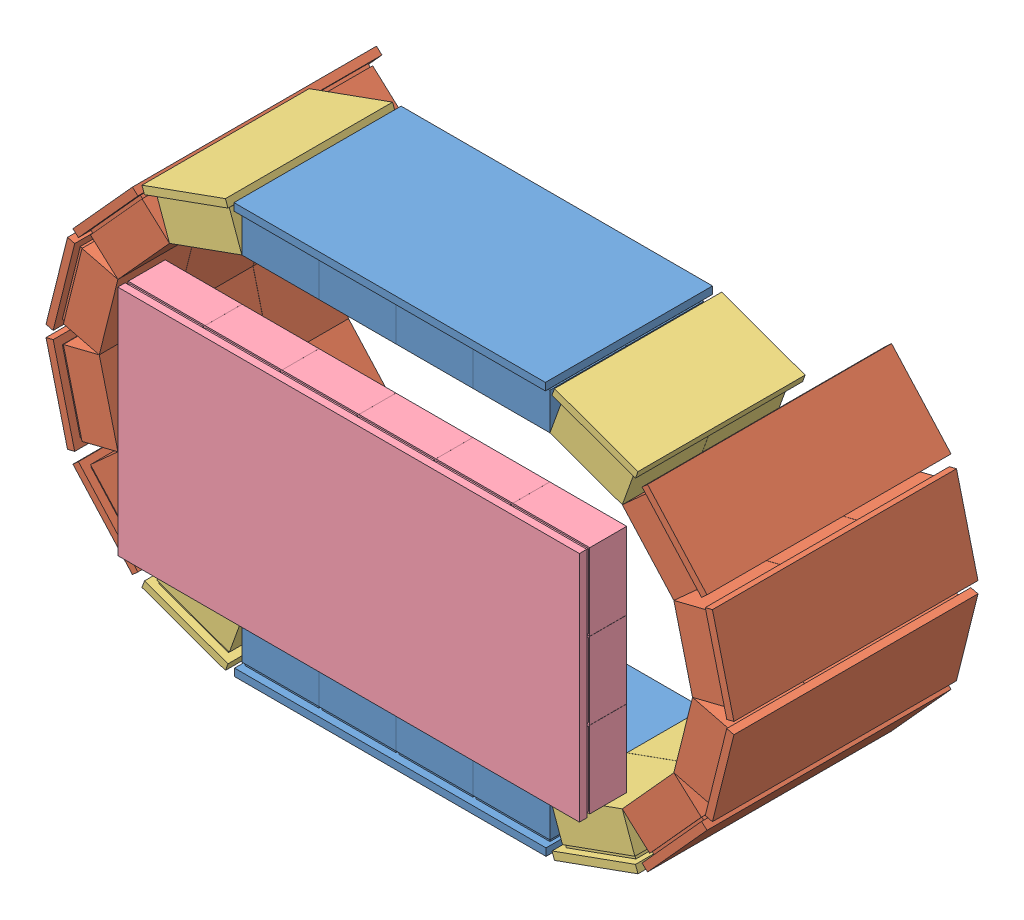
SolidWorks assembly detectorassem, configuration Default. Lengths in mm.
Overall size (517.67 317.54 193).
17 component instances, 4 part files, 15 mates.
Components (placement in the parent):
- 52mmTOPBOTTOM-1: 52mmTOPBOTTOM [Default] at (-69.8528 -35.4842 8.7442) size (210.55 32 113)
- SideDetector-1: SideDetector [Default] at (215.9367 233.9438 -54.2197) x (-0.242515 0.970148 0) z (0 0 1) size (268 155.36 165)
  - 52mmX4-1: 52mmX4 [Default] at (-99.1405 6.5957 36.9639) size (60 32 165)
  - 52mmX4-2: 52mmX4 [Default] at (-35.1412 22.594 36.9639) x (0.882373 0.47055 0) z (0 0 1) size (60 32 165)
  - 52mmX4-3: 52mmX4 [Default] at (-163.1399 22.594 36.9639) x (0.882373 -0.47055 0) z (0 0 1) size (60 32 165)
  - 52mmX4-4: 52mmX4 [Default] at (-212.0831 66.8254 36.9639) x (0.557166 -0.830401 0) z (0 0 1) size (60 32 165)
  - 52mmX3-1: 52mmX3 [Default] at (-234.4563 128.8843 62.9639) x (0.100883 -0.994898 0) z (0 0 1) size (60 32 113)
  - 52mmX3-2: 52mmX3 [Default] at (13.802 66.8254 62.9639) x (0.557166 0.830401 0) z (0 0 1) size (60 32 113)
- SideDetector-2: SideDetector [Default] at (-199.3424 -27.5859 -54.2197) x (0.242515 -0.970148 0) z (0 0 1) size (268 155.36 165)
  - 52mmX4-1: 52mmX4 [Default] at (-99.1405 6.5957 36.9639) size (60 32 165)
  - 52mmX4-2: 52mmX4 [Default] at (-35.1412 22.594 36.9639) x (0.882373 0.47055 0) z (0 0 1) size (60 32 165)
  - 52mmX4-3: 52mmX4 [Default] at (-163.1399 22.594 36.9639) x (0.882373 -0.47055 0) z (0 0 1) size (60 32 165)
  - 52mmX4-4: 52mmX4 [Default] at (-212.0831 66.8254 36.9639) x (0.557166 -0.830401 0) z (0 0 1) size (60 32 165)
  - 52mmX3-1: 52mmX3 [Default] at (-234.4563 128.8843 62.9639) x (0.100883 -0.994898 0) z (0 0 1) size (60 32 113)
  - 52mmX3-2: 52mmX3 [Default] at (13.802 66.8254 62.9639) x (0.557166 0.830401 0) z (0 0 1) size (60 32 113)
- 52mmTOPBOTTOM-2: 52mmTOPBOTTOM [Default] at (86.4472 241.8421 8.7442) x (-1 0 0) z (0 0 1) size (210.55 32 113)
- 52mmAnterior-2: 52mmAnterior [Default] at (34.3328 154.0821 93.2442) x (1 0 0) z (0 1 0) size (312.06 32 157.26)
Mates (geometry in assembly coordinates):
- Coincident1: coincident anti-aligned: line of 52mmTOPBOTTOM-1 through (112.4472 -3.4842 61.2442) axis (0 0 -1); line of SideDetector-1/52mmX3-1 through (112.4472 -3.4842 9.3442) axis (0 0 1)
- Coincident2: coincident: point of 52mmTOPBOTTOM-1; point of SideDetector-1/52mmX3-1
- Parallel1: parallel anti-aligned: line of 52mmTOPBOTTOM-1 through (-43.7528 -3.4842 61.2442) axis (1 0 0); line of 52mmTOPBOTTOM-2 through (8.2472 209.8421 61.2442) axis (-1 0 0)
- Parallel2: parallel anti-aligned: line of 52mmTOPBOTTOM-1 through (-95.8528 -3.4842 9.3442) axis (0 0 1); line of 52mmTOPBOTTOM-2 through (-95.8528 209.8421 61.2442) axis (0 0 -1)
- Coincident5: coincident anti-aligned: line of 52mmTOPBOTTOM-1 through (-95.8528 -3.4842 9.3442) axis (0 0 1); line of SideDetector-2/52mmX3-2 through (-95.8528 -3.4842 61.2442) axis (0 0 -1)
- Coincident6: coincident: point of 52mmTOPBOTTOM-1; point of SideDetector-2/52mmX3-2
- Coincident7: coincident anti-aligned: line of SideDetector-2/52mmX3-1 through (-95.8528 209.8421 9.3442) axis (0 0 1); line of 52mmTOPBOTTOM-2 through (-95.8528 209.8421 61.2442) axis (0 0 -1)
- Coincident8: coincident anti-aligned: line of SideDetector-1/52mmX3-2 through (112.4472 209.8421 61.2442) axis (0 0 -1); line of 52mmTOPBOTTOM-2 through (112.4472 209.8421 9.3442) axis (0 0 1)
- Coincident9: coincident: point of SideDetector-2/52mmX3-1; point of 52mmTOPBOTTOM-2
- Coincident11: coincident anti-aligned: line of 52mmTOPBOTTOM-1 through (-95.8528 -3.4842 61.2442) axis (0 -1 0); line of 52mmTOPBOTTOM-2 through (-95.8528 209.8421 61.2442) axis (0 1 0)
- Perpendicular1: perpendicular: plane of 52mmTOPBOTTOM-2 through (60.3472 209.8421 61.2442) normal (0 0 1); plane of 52mmAnterior-2 through (8.4727 181.0821 61.2442) normal (0 1 0)
- Perpendicular2: perpendicular: plane of SideDetector-1/52mmX4-1 through (208.8416 103.1789 61.2442) normal (0 0 1); plane of 52mmAnterior-2 through (164.4927 77.1821 61.2442) normal (1 0 0)
- Coincident15: coincident: plane of 52mmTOPBOTTOM-1 through (8.3472 -3.4842 61.2442) normal (0 0 1); plane of 52mmAnterior-2 through (34.4727 -53.9179 61.2442) normal (0 0 -1)
- Distance2: distance = 28.76 mm: line of 52mmAnterior-2 through (8.3328 181.0821 61.2442) axis (1 0 0); line of 52mmTOPBOTTOM-2 through (60.3472 209.8421 61.2442) axis (-1 0 0)
- Distance3: distance = 44.55 mm: point of SideDetector-2/52mmX4-1; line of 52mmAnterior-2 through (-147.6972 77.1821 61.2442) axis (0 1 0)
